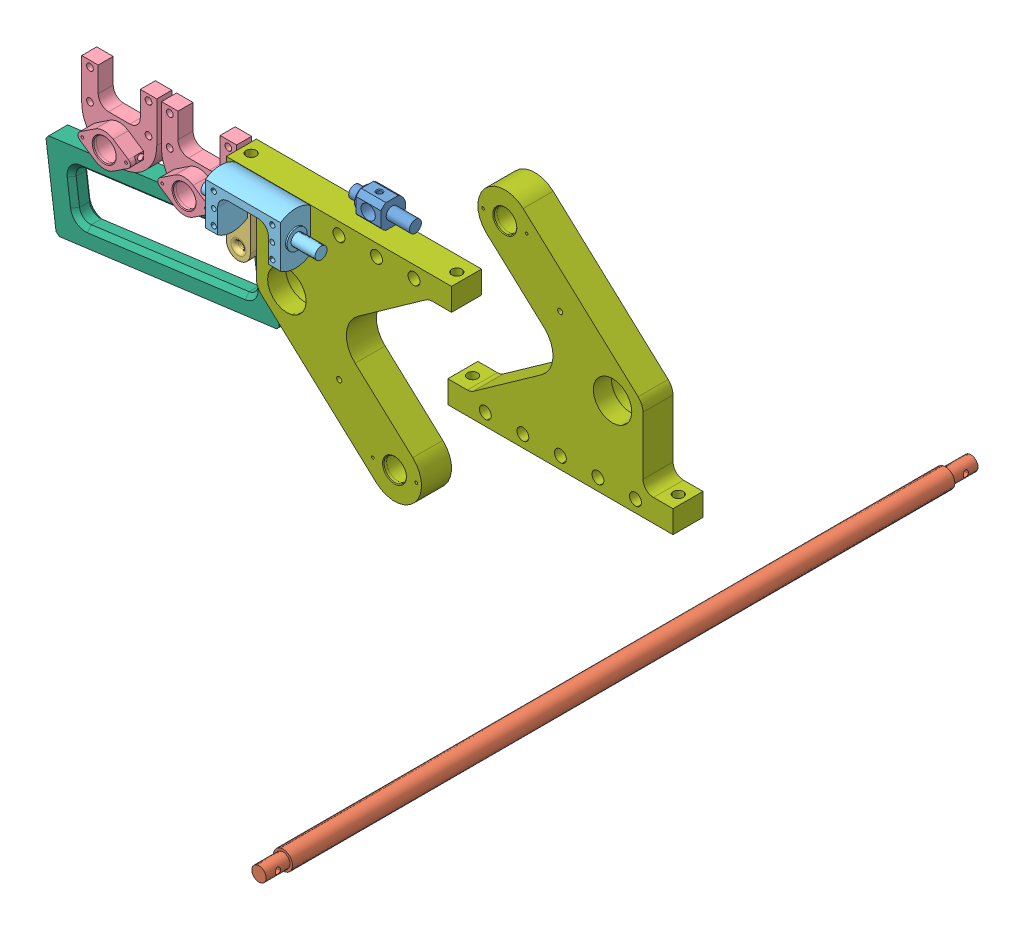
SolidWorks assembly Waterjet Layout, configuration Default. Lengths in mm.
Overall size (472.7 256.46 474.2).
9 component instances, 7 part files, 12 mates.
Components (placement in the parent):
- LAS-01-0002-1: LAS-01-0002 [Default] at (-11.1243 21.5161 56.638) size (40.5 16 16.5)
- LAS-01-0004-1: LAS-01-0004 [Default] at (184.9082 -127.8779 -124.2759) size (12.7 12.7 474.2)
- LAS-01-0006-1: LAS-01-0006 [Default] at (-104 -48.175 42.7255) size (16 38 15)
- LAS-02-0002-1: LAS-02-0002 [Default] at (-140.175 -37 37.7255) size (50 52 20)
- LAS-02-0006-1: LAS-02-0006 [Default] at (21.3833 88.0616 169.9961) size (76 34.41 20)
- LAS-03-0002-1: LAS-03-0002 [Default] at (-203.4849 -114.0954 -4.0178) x (0.131112 -0.991368 0) z (0 0 1) size (55 150 12.7)
- LAS-03-0004-1: LAS-03-0004 [Default] at (73.5102 -69.5 37.7255) size (150 143 20)
- LAS-03-0004-2: LAS-03-0004 [Default] at (0 0 37.7255) x (-1 0 0) z (0 0 1) size (150 143 20)
- LAS-02-0002-3: LAS-02-0002 [Default] at (-193.35 -37 37.7255) size (50 52 20)
Mates (geometry in assembly coordinates):
- Coincident6: coincident aligned: plane of LAS-02-0002-1 through (-165.175 0 57.7255) normal (0 1 0); plane of LAS-03-0004-2 through (38 0 57.7255) normal (0 1 0)
- Coincident11: coincident anti-aligned: plane of LAS-03-0004-2 through (0 0 37.7255) normal (-1 0 0)
- Coincident13: coincident anti-aligned: plane of LAS-03-0004-2 through (0 0 37.7255) normal (0 -1 0)
- Tangent3: tangent: cylinder of LAS-03-0004-1 through (73.5102 -17.5 57.7255) axis (0 0 -1) radius 17.5; plane of LAS-03-0004-2 through (50 0 57.7255) normal (0 1 0)
- Parallel2: parallel anti-aligned: plane of LAS-03-0004-1 through (35.5102 -69.5 57.7255) normal (0 -1 0); plane of LAS-03-0004-2 through (38 0 57.7255) normal (0 1 0)
- Coincident16: coincident aligned: plane of LAS-03-0004-1 through (73.5102 55.5 57.7255) normal (0 0 1); plane of LAS-03-0004-2 through (0 -125 57.7255) normal (0 0 1)
- Coincident17: coincident aligned: plane of LAS-02-0002-1 through (-165.175 0 57.7255) normal (0 1 0); plane of LAS-03-0004-2 through (38 0 57.7255) normal (0 1 0)
- Coincident18: coincident aligned: plane of LAS-02-0002-1 through (-140.175 -37 37.7255) normal (0 0 -1); plane of LAS-03-0004-2 through (0 -125 37.7255) normal (0 0 -1)
- Distance13: distance = 3.175 mm anti-aligned: plane of LAS-02-0002-1 through (-115.175 -52 57.7255) normal (1 0 0); plane of LAS-03-0004-2 through (-112 0 57.7255) normal (-1 0 0)
- Coincident20: coincident aligned: plane of LAS-01-0006-1 through (-104 -48.175 57.7255) normal (0 0 1); plane of LAS-02-0002-1 through (-140.175 -37 57.7255) normal (0 0 1)
- Distance14: distance = 3.175 mm anti-aligned: plane of LAS-03-0004-2 through (-112 -15 57.7255) normal (0 -1 0); plane of LAS-01-0006-1 through (-96 -18.175 57.7255) normal (0 1 0)
- Distance15: distance = 3.175 mm anti-aligned: plane of LAS-02-0002-1 through (-115.175 -52 57.7255) normal (1 0 0); plane of LAS-01-0006-1 through (-112 -36.175 57.7255) normal (-1 0 0)
